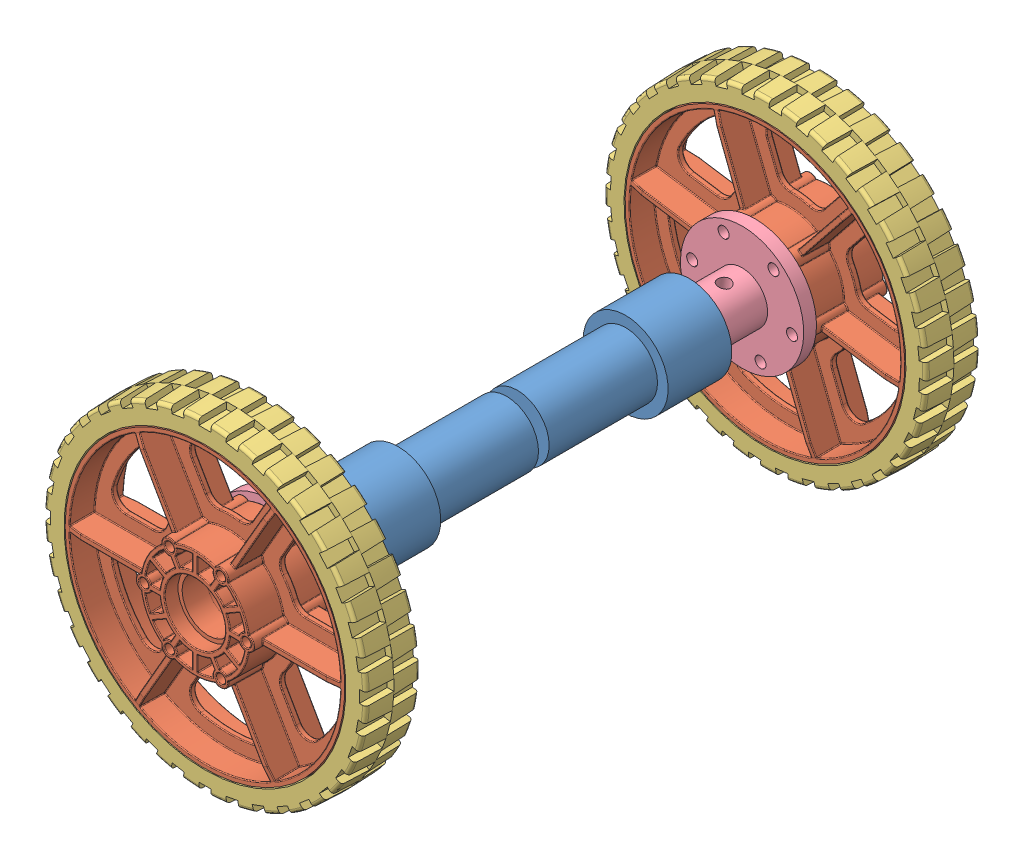
SolidWorks assembly Minibot Alpha, configuration Default. Lengths in mm.
Overall size (173.93 173.93 298.46).
10 component instances, 4 part files, 6 mates.
Components (placement in the parent):
- Mock Motor-1: Mock Motor [Default] at origin size (40 40 101.3)
- Tetrix 6in High Grip Wheel-1: Tetrix 6in High Grip Wheel [Default] at (19.6843 -12.5833 4.3821) x (0 0 1) z (-0.988223 0.153018 0) size (61.33 152.4 152.4)
  - 6 wheel Rev 4-1: 6 wheel Rev 4 [Default] at (-52.6446 9.4231 21.378) size (34.93 132.08 132.08)
  - 6 wheel tread II-1: 6 wheel tread II [Default] at (-65.3446 9.4231 21.378) x (0 0 -1) z (1 0 0) size (152.4 152.4 25.58)
  - 6mm Hub-1: 6mm Hub [Default] at (-35.1821 9.4231 21.378) x (0 -0.999986 -0.005317) z (0 -0.005317 0.999986) size (58 26.4 58)
- Mock Motor-4: Mock Motor [Default] at (0 0 167) x (-0.923728 -0.383049 0) z (0 0 -1) size (40 40 101.3)
- Tetrix 6in High Grip Wheel-2: Tetrix 6in High Grip Wheel [Default] at (-21.378 -9.4231 162.6179) x (0 0 -1) z (1 0 0) size (61.33 152.4 152.4)
  - 6 wheel Rev 4-1: 6 wheel Rev 4 [Default] at (-52.6446 9.4231 21.378) size (34.93 132.08 132.08)
  - 6 wheel tread II-1: 6 wheel tread II [Default] at (-65.3446 9.4231 21.378) x (0 0 -1) z (1 0 0) size (152.4 152.4 25.58)
  - 6mm Hub-1: 6mm Hub [Default] at (-35.1821 9.4231 21.378) x (0 -0.999986 -0.005317) z (0 -0.005317 0.999986) size (58 26.4 58)
Mates (geometry in assembly coordinates):
- Concentric1: concentric aligned: cylinder of Mock Motor-1 through (0 0 -20.3) axis (0 0 1) radius 3; cylinder of Tetrix 6in High Grip Wheel-1/6mm Hub-1 through (0 0 -44.612) axis (0 0 1) radius 3
- Distance1: distance = 4.4 mm anti-aligned: plane of Tetrix 6in High Grip Wheel-1/6mm Hub-1 through (0 0 -4.4) normal (0 0 1); plane of Mock Motor-1 through (0 0 0) normal (0 0 -1)
- Concentric2: concentric anti-aligned: cylinder of Mock Motor-1 through (0 0 81) axis (0 0 -1) radius 15; cylinder of Mock Motor-4 through (0 0 86) axis (0 0 1) radius 15
- Distance2: distance = 5 mm anti-aligned: plane of Mock Motor-1 through (0 0 81) normal (0 0 1); plane of Mock Motor-4 through (0 0 86) normal (0 0 -1)
- Concentric4: concentric aligned: cylinder of Mock Motor-4 through (0 0 187.3) axis (0 0 -1) radius 3; cylinder of Tetrix 6in High Grip Wheel-2/6mm Hub-1 through (0 0 211.612) axis (0 0 -1) radius 3
- Distance3: distance = 4.4 mm anti-aligned: plane of Tetrix 6in High Grip Wheel-2/6mm Hub-1 through (0 0 171.4) normal (0 0 -1); plane of Mock Motor-4 through (0 0 167) normal (0 0 1)
